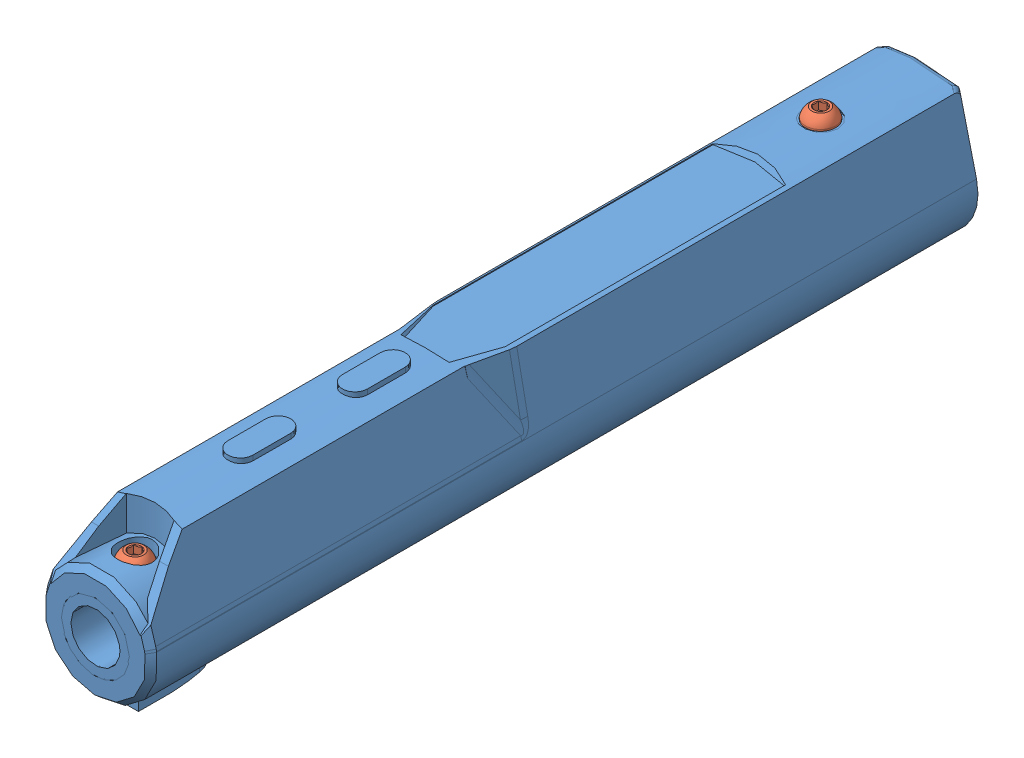
SolidWorks assembly Assem1, configuration Default. Lengths in mm.
Overall size (13 19.07 96.77).
4 component instances, 2 part files, 7 mates.
Components (placement in the parent):
- ts100_body-1: ts100_body [Default] at origin size (13 18.32 96.77)
- 92095A110_BUTTON HEAD HEX DRIVE SCREW-1: 92095A110_BUTTON HEAD HEX DRIVE SCREW [92095A110] at (0 6.45 92.2) x (-0.600588 0 0.799558) z (0 1 0) size (3.5 3.5 3.5)
- 92095A110_BUTTON HEAD HEX DRIVE SCREW-2: 92095A110_BUTTON HEAD HEX DRIVE SCREW [92095A110] at (0 11.28 12.6) x (-0.999783 0 -0.020854) z (0 1 0) size (3.5 3.5 3.5)
- 92095A110_BUTTON HEAD HEX DRIVE SCREW-3: 92095A110_BUTTON HEAD HEX DRIVE SCREW [92095A110] at (0 -7.6 92.2) x (-0.761822 0 -0.647786) z (0 -1 0) size (3.5 3.5 3.5)
Mates (geometry in assembly coordinates):
- Coincident1: coordinate: point of ts100_body-1; point of assembly
- Concentric1: concentric: cylinder of ts100_body-1 through (0 5.15 92.2) axis (0 1 0) radius 2; cylinder of 92095A110_BUTTON HEAD HEX DRIVE SCREW-1 through (0 6.45 92.2) axis (0 1 0) radius 1.75
- Coincident2: coincident: plane of ts100_body-1 through (0 5.15 92.2) normal (0 1 0); plane of 92095A110_BUTTON HEAD HEX DRIVE SCREW-1 through (-1.3992 5.15 91.149) normal (0 -1 0)
- Concentric2: concentric: cylinder of ts100_body-1 through (0 9.98 12.6) axis (0 1 0) radius 2; cylinder of 92095A110_BUTTON HEAD HEX DRIVE SCREW-2 through (0 11.28 12.6) axis (0 1 0) radius 1.75
- Coincident3: coincident: plane of ts100_body-1 through (0 9.98 12.6) normal (0 1 0); plane of 92095A110_BUTTON HEAD HEX DRIVE SCREW-2 through (0.0365 9.98 10.8504) normal (0 -1 0)
- Concentric3: concentric: cylinder of ts100_body-1 through (0 -6.3 92.2) axis (0 -1 0) radius 2; cylinder of 92095A110_BUTTON HEAD HEX DRIVE SCREW-3 through (0 -7.6 92.2) axis (0 -1 0) radius 1.75
- Coincident4: coincident: plane of ts100_body-1 through (0 -6.3 92.2) normal (0 -1 0); plane of 92095A110_BUTTON HEAD HEX DRIVE SCREW-3 through (-1.1336 -6.3 93.5332) normal (0 1 0)
